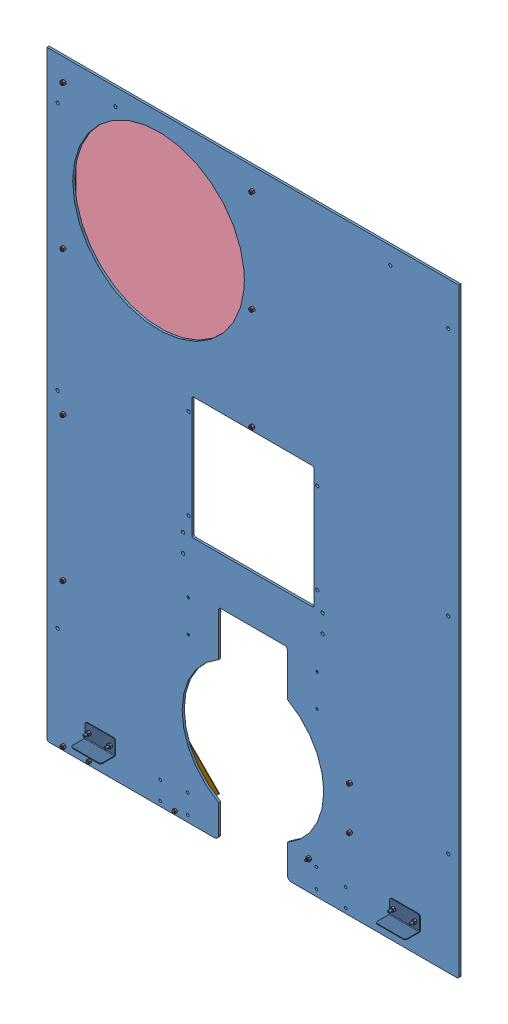
SolidWorks assembly GE-19156, configuration Default. Lengths in mm.
Overall size (1219.2 1778 85.73).
70 component instances, 22 part files, 143 mates.
Components (placement in the parent):
- GE-19157-4: GE-19157 [Default] at origin size (1219.2 1778 6.35)
- GE-19134-1: GE-19134 [Default] at (63.5 0 -6.35) x (-1 0 0) z (0 0 -1) size (25.4 1727.2 12.7)
- GE-19135-1: GE-19135 [Default] at (596.9 1098.55 -6.35) x (-1 0 0) z (0 0 -1) size (25.4 628.65 12.7)
- GE-19158-2: GE-19158 [Default] at (38.1 0 -28.575) size (584.2 1727.2 6.35)
- GE-19138-1: GE-19138 [Default] at (0 0 -19.05) size (406.4 120.65 12.7)
- GE-19139-2: GE-19139 [Default] at (1216.025 520.7 -31.75) x (-1 0 0) z (0 0 1) size (50.8 152.4 25.4)
- GE-19140-1: GE-19140 [Default] at (777.6052 88.9 -6.35) x (-0.923728 -0.383049 0) z (0 0 -1) size (25.4 25.4 25.4)
- GE-19190-1: GE-19190 [Default] at (838.1961 233.6306 -81.6653) x (0 0 -1) z (0 1 0) size (6.35 44.45 152.4)
  - GE-19190-1-1: GE-19190-1 [Default] at (-48.3278 -36.5164 -30.4306) size (6.35 19.05 152.4)
  - GE-19190-2-1: GE-19190-2 [Default] at (-50.709 -46.4642 60.9432) x (0 0 1) z (-1 0 0) size (152.4 28.57 3.17)
- GE-19190-2: GE-19190 [Default] at (371.4789 325.1694 -78.4903) x (0 0 -1) z (0 -1 0) size (6.35 44.45 152.4)
  - GE-19190-1-1: GE-19190-1 [Default] at (-48.3278 -36.5164 -30.4306) size (6.35 19.05 152.4)
  - GE-19190-2-1: GE-19190-2 [Default] at (-50.709 -46.4642 60.9432) x (0 0 1) z (-1 0 0) size (152.4 28.57 3.17)
- GE-19190-3: GE-19190 [Default] at (391.163 173.6734 -78.4903) x (0 0 -1) z (0.707107 -0.707107 0) size (6.35 44.45 152.4)
  - GE-19190-1-1: GE-19190-1 [Default] at (-48.3278 -36.5164 -30.4306) size (6.35 19.05 152.4)
  - GE-19190-2-1: GE-19190-2 [Default] at (-50.709 -46.4642 60.9432) x (0 0 1) z (-1 0 0) size (152.4 28.57 3.17)
- GE-19142-1: GE-19142 [Default] at (203.2 63.5 0) x (-1 0 0) z (0 0 -1) size (88.9 44.45 44.45)
- GE-19142-2: GE-19142 [Default] at (1104.9 63.5 0) x (-1 0 0) z (0 0 -1) size (88.9 44.45 44.45)
- hex_.25_20_1.5-1: hex_.25_20_1.5 [92865A546] at (50.8 1714.5 -11.5094) x (0 0 1) z (1 0 0) size (42.07 12.83 11.11)
- nylock_10_32-1: nylock_10_32 [90631A411] at (342.9 215.9 -30.1625) x (-0.98095 -0.194258 0) z (0.194258 -0.98095 0) size (9.53 5.95 11)
- nylock_.25_20-13: nylock_.25_20 [Default] at (1028.7 85.725 1.9812) x (-0.972777 -0.231744 0) z (-0.231744 0.972777 0) size (11.11 7.94 12.83)
- nylock_.25_20-14: nylock_.25_20 [Default] at (1092.2 85.725 1.9812) x (-0.994367 -0.105992 0) z (-0.105992 0.994367 0) size (11.11 7.94 12.83)
- nylock_.25_20-15: nylock_.25_20 [Default] at (127 85.725 1.9812) x (-0.999918 -0.012843 0) z (-0.012843 0.999918 0) size (11.11 7.94 12.83)
- nylock_.25_20-16: nylock_.25_20 [Default] at (190.5 85.725 1.9812) x (-0.999134 0.04161 0) z (0.04161 0.999134 0) size (11.11 7.94 12.83)
- flat_hex_.25_20_1-1: flat_hex_.25_20_1 [91253A542] at (1092.2 85.725 -6.35) x (1 0 0) z (0 0 -1) size (13.49 13.49 25.61)
- flat_hex_.25_20_1-2: flat_hex_.25_20_1 [91253A542] at (1028.7 85.725 -6.35) x (0.987351 -0.158553 0) z (0 0 -1) size (13.49 13.49 25.61)
- flat_hex_.25_20_1-3: flat_hex_.25_20_1 [91253A542] at (190.5 85.725 -6.35) x (0.959125 -0.282984 0) z (0 0 -1) size (13.49 13.49 25.61)
- flat_hex_.25_20_1-4: flat_hex_.25_20_1 [91253A542] at (127 85.725 -6.35) x (0.928571 -0.371154 0) z (0 0 -1) size (13.49 13.49 25.61)
- nylock_.25_20-17: nylock_.25_20 [Default] at (777.6052 88.9 0) x (0.809812 0.58669 0) z (0.58669 -0.809812 0) size (11.11 7.94 12.83)
- button_hex_.25_20_1.25-1: button_hex_.25_20_1.25 [Default] at (777.6052 88.9 -22.4028) x (0.923728 0.383049 0) z (0 0 -1) size (11.1 11.1 35.11)
- flat_hex_10_32_.625-1: flat_hex_10_32_.625 [Default] at (342.9 215.9 -22.225) x (0.923728 -0.383049 0) z (0 0 1) size (10.44 10.44 15.88)
- flat_hex_10_32_1.375-3: flat_hex_10_32_1.375 [Default] at (866.775 215.9 -6.35) x (-0.923728 0.383049 0) z (0 0 1) size (10.44 10.44 34.93)
- flat_hex_10_32_1.375-2: flat_hex_10_32_1.375 [Default] at (866.775 342.9 -6.35) x (-0.85131 0.524663 0) z (0 0 1) size (10.44 10.44 34.93)
- hex_.25_20_1.5-13: hex_.25_20_1.5 [92865A546] at (50.8 1289.05 -11.5094) x (0 0 1) z (0.987351 0.158553 0) size (42.07 12.83 11.11)
- hex_.25_20_1.5-14: hex_.25_20_1.5 [92865A546] at (50.8 863.6 -11.5094) x (0 0 1) z (0.959125 0.282984 0) size (42.07 12.83 11.11)
- hex_.25_20_1.5-15: hex_.25_20_1.5 [92865A546] at (50.8 438.15 -11.5094) x (0 0 1) z (0.928571 0.371154 0) size (42.07 12.83 11.11)
- hex_.25_20_1.5-16: hex_.25_20_1.5 [92865A546] at (50.8 12.7 -11.5094) x (0 0 1) z (0.906989 0.421154 0) size (42.07 12.83 11.11)
- hex_.25_20_1.5-19: hex_.25_20_1.5 [92865A546] at (609.6 1714.5 -11.5094) x (0 0 1) z (0.952324 0.305088 0) size (42.07 12.83 11.11)
- hex_.25_20_1.5-20: hex_.25_20_1.5 [92865A546] at (609.6 1412.875 -11.5094) x (0 0 1) z (0.985697 0.168526 0) size (42.07 12.83 11.11)
- hex_.25_20_1.5-21: hex_.25_20_1.5 [92865A546] at (609.6 1111.25 -11.5094) x (0 0 1) z (1 0 0) size (42.07 12.83 11.11)
- hex_.25_20_1.5-22: hex_.25_20_1.5 [92865A546] at (898.525 342.9 -14.6844) x (0 0 1) z (-0.845962 0.533243 0) size (42.07 12.83 11.11)
- hex_.25_20_1.5-24: hex_.25_20_1.5 [92865A546] at (898.525 215.9 -14.6844) x (0 0 1) z (-0.762825 0.646605 0) size (42.07 12.83 11.11)
- nylock_.25_20-18: nylock_.25_20 [Default] at (50.8 1714.5 0) x (1 0 0) z (0 -1 0) size (11.11 7.94 12.83)
- nylock_.25_20-19: nylock_.25_20 [Default] at (50.8 1289.05 0) x (0.987351 0.158553 0) z (0.158553 -0.987351 0) size (11.11 7.94 12.83)
- nylock_.25_20-20: nylock_.25_20 [Default] at (50.8 863.6 0) x (0.959125 0.282984 0) z (0.282984 -0.959125 0) size (11.11 7.94 12.83)
- nylock_.25_20-21: nylock_.25_20 [Default] at (50.8 438.15 0) x (0.928571 0.371154 0) z (0.371154 -0.928571 0) size (11.11 7.94 12.83)
- nylock_.25_20-22: nylock_.25_20 [Default] at (50.8 12.7 0) x (0.906989 0.421154 0) z (0.421154 -0.906989 0) size (11.11 7.94 12.83)
- nylock_.25_20-25: nylock_.25_20 [Default] at (609.6 1714.5 0) x (0.952324 0.305088 0) z (0.305088 -0.952324 0) size (11.11 7.94 12.83)
- nylock_.25_20-26: nylock_.25_20 [Default] at (609.6 1412.875 0) x (0.985697 0.168526 0) z (0.168526 -0.985697 0) size (11.11 7.94 12.83)
- nylock_.25_20-27: nylock_.25_20 [Default] at (609.6 1111.25 0) x (1 0 0) z (0 -1 0) size (11.11 7.94 12.83)
- nylock_.25_20-30: nylock_.25_20 [Default] at (898.525 342.9 0) x (0.987351 0.158553 0) z (0.158553 -0.987351 0) size (11.11 7.94 12.83)
- nylock_.25_20-32: nylock_.25_20 [Default] at (898.525 215.9 0) x (0.959125 0.282984 0) z (0.282984 -0.959125 0) size (11.11 7.94 12.83)
- nylock_10_32-12: nylock_10_32 [90631A411] at (342.9 342.9 -30.1625) x (-0.937742 -0.347333 0) z (0.347333 -0.937742 0) size (9.53 5.95 11)
- nylock_10_32-15: nylock_10_32 [90631A411] at (358.4172 166.0026 -30.1625) x (-0.885882 -0.463911 0) z (0.463911 -0.885882 0) size (9.53 5.95 11)
- nylock_10_32-14: nylock_10_32 [90631A411] at (448.2197 76.2 -30.1625) x (-0.838783 -0.544466 0) z (0.544466 -0.838783 0) size (9.53 5.95 11)
- nylock_10_32-13: nylock_10_32 [90631A411] at (866.775 342.9 -33.3375) x (-0.807899 -0.589321 0) z (0.589321 -0.807899 0) size (9.53 5.95 11)
- nylock_10_32-11: nylock_10_32 [90631A411] at (866.775 215.9 -33.3375) x (-0.802128 -0.597152 0) z (0.597152 -0.802128 0) size (9.53 5.95 11)
- flat_hex_10_32_.625-8: flat_hex_10_32_.625 [Default] at (342.9 342.9 -22.225) x (0.972777 -0.231744 0) z (0 0 1) size (10.44 10.44 15.88)
- flat_hex_10_32_.625-6: flat_hex_10_32_.625 [Default] at (358.4172 166.0026 -22.225) x (0.994367 -0.105992 0) z (0 0 1) size (10.44 10.44 15.88)
- flat_hex_10_32_.625-7: flat_hex_10_32_.625 [Default] at (448.2197 76.2 -22.225) x (0.999918 -0.012843 0) z (0 0 1) size (10.44 10.44 15.88)
- VisionTape-1: VisionTape [Default] at (795.3119 461.6361 -6.35) x (-0.968246 -0.25 0) z (0 0 -1) size (50.8 139.7 0.79)
- VisionTape-2: VisionTape [Default] at (473.075 448.9361 -6.35) x (-0.968246 0.25 0) z (0 0 -1) size (50.8 139.7 0.79)
- GE-19251-1: GE-19251 [Default] at (38.1 0 -22.225) size (25.4 1727.2 3.17)
- GE-19252-1: GE-19252 [Default] at (622.3 1098.55 -22.225) size (25.4 628.65 3.17)
- round_hex_flange_10_32_1.5_partial-1: round_hex_flange_10_32_1.5_partial [Default] at (381 12.7 -31.1404) x (-0.923728 -0.383049 0) z (0 0 -1) size (10.34 10.34 40.67)
- round_hex_flange_10_32_1.5_partial-2: round_hex_flange_10_32_1.5_partial [Default] at (127 12.7 -31.1404) x (-0.923728 -0.383049 0) z (0 0 -1) size (10.34 10.34 40.67)
- nylock_10_32-16: nylock_10_32 [90631A411] at (381 12.7 0) x (1 0 0) z (0 -1 0) size (9.53 5.95 11)
- nylock_10_32-17: nylock_10_32 [90631A411] at (127 12.7 0) x (1 0 0) z (0 -1 0) size (9.53 5.95 11)
- GE-19253-1: GE-19253 [92805K33] at (381 12.7 -28.575) x (-0.923728 -0.383049 0) z (-0.383049 0.923728 0) size (7.81 25.4 7.81)
- GE-19253-2: GE-19253 [92805K33] at (127 12.7 -28.575) x (-0.923728 -0.383049 0) z (-0.383049 0.923728 0) size (7.81 25.4 7.81)
Mates (geometry in assembly coordinates):
- Concentric4: concentric: cylinder of GE-19134-1 through (50.8 1714.5 -6.35) axis (0 0 -1) radius 3.3655; cylinder of GE-19157-4 through (50.8 1714.5 0) axis (0 0 -1) radius 3.3655
- Coincident9: coincident: plane of GE-19139-2 through (1216.025 520.7 -31.75) normal (0 0 -1); plane of GE-19190-1/GE-19190-1-1 through (860.425 355.6 -31.75) normal (0 0 1)
- Concentric10: concentric: cylinder of GE-19139-2 through (866.775 342.9 -6.35) axis (0 0 1) radius 2.8067; cylinder of GE-19190-1/GE-19190-1-1 through (866.775 342.9 -33.3375) axis (0 0 1) radius 2.5797
- Concentric11: concentric: cylinder of GE-19139-2 through (866.775 215.9 -6.35) axis (0 0 1) radius 2.8067; cylinder of GE-19190-1/GE-19190-1-1 through (866.775 215.9 -33.3375) axis (0 0 1) radius 2.5797
- Coincident10: coincident: plane of GE-19158-2 through (38.1 0 -28.575) normal (0 0 -1); plane of GE-19190-2/GE-19190-1-1 through (349.25 203.2 -28.575) normal (0 0 1)
- Coincident11: coincident: plane of GE-19158-2 through (38.1 0 -28.575) normal (0 0 -1); plane of GE-19190-3/GE-19190-1-1 through (461.6901 71.7099 -28.575) normal (0 0 1)
- Concentric14: concentric: cylinder of GE-19158-2 through (358.4172 166.0026 -22.225) axis (0 0 1) radius 2.8067; cylinder of GE-19190-3/GE-19190-1-1 through (358.4172 166.0026 -30.1625) axis (0 0 1) radius 2.5797
- Concentric15: concentric: cylinder of GE-19190-3/GE-19190-1-1 through (448.2197 76.2 -30.1625) axis (0 0 1) radius 2.5797; cylinder of GE-19158-2 through (448.2197 76.2 -22.225) axis (0 0 1) radius 2.8067
- Coincident14: coincident: plane of assembly; plane of assembly; plane of GE-19158-2 through (38.1 0 -28.575) normal (0 0 -1); plane of hex_.25_20_1.5-1 through (56.3562 1711.2921 -28.575) normal (0 0 1)
- Concentric19: concentric: cylinder of assembly; cylinder of assembly; cylinder of GE-19158-2 through (50.8 1714.5 -22.225) axis (0 0 1) radius 3.3782; cylinder of hex_.25_20_1.5-1 through (50.8 1714.5 -28.575) axis (0 0 1) radius 3.175
- Concentric43: concentric: cylinder of GE-19190-2/GE-19190-1-1 through (342.9 215.9 -30.1625) axis (0 0 1) radius 2.5797; cylinder of nylock_10_32-1 through (342.9 215.9 -35.1996) axis (0 0 1) radius 2.0454
- Coincident42: coincident: plane of GE-19190-2/GE-19190-1-1 through (354.0125 203.2 -30.1625) normal (0 0 -1); plane of nylock_10_32-1 through (341.8317 221.2945 -30.1625) normal (0 0 1)
- Concentric44: concentric: cylinder of assembly; cylinder of assembly; cylinder of nylock_10_32-1 through (342.9 215.9 -35.1996) axis (0 0 1) radius 2.0454; cylinder of flat_hex_10_32_.625-1 through (342.9 215.9 -22.225) axis (0 0 1) radius 5.2197
- Coincident50: coincident: plane of assembly; plane of assembly; plane of GE-19142-2 through (1016 65.4812 1.9812) normal (0 0 1); plane of nylock_.25_20-13 through (1028.7 85.725 1.9812) normal (0 0 -1)
- Concentric55: concentric: cylinder of assembly; cylinder of assembly; cylinder of GE-19142-2 through (1028.7 85.725 88.9) axis (0 0 -1) radius 3.3782; cylinder of nylock_.25_20-13 through (1028.7 85.725 1.9812) axis (0 0 1) radius 3.175
- Coincident51: coincident: plane of assembly; plane of assembly; plane of GE-19142-2 through (1016 65.4812 1.9812) normal (0 0 1); plane of nylock_.25_20-14 through (1092.2 85.725 1.9812) normal (0 0 -1)
- Concentric56: concentric: cylinder of assembly; cylinder of assembly; cylinder of GE-19142-2 through (1092.2 85.725 88.9) axis (0 0 -1) radius 3.3782; cylinder of nylock_.25_20-14 through (1092.2 85.725 1.9812) axis (0 0 1) radius 3.175
- Coincident52: coincident: plane of assembly; plane of assembly; plane of GE-19142-1 through (114.3 65.4812 1.9812) normal (0 0 1); plane of nylock_.25_20-15 through (127 85.725 1.9812) normal (0 0 -1)
- Concentric57: concentric: cylinder of assembly; cylinder of assembly; cylinder of GE-19142-1 through (127 85.725 88.9) axis (0 0 -1) radius 3.3782; cylinder of nylock_.25_20-15 through (127 85.725 1.9812) axis (0 0 1) radius 3.175
- Coincident53: coincident: plane of assembly; plane of assembly; plane of GE-19142-1 through (114.3 65.4812 1.9812) normal (0 0 1); plane of nylock_.25_20-16 through (190.5 85.725 1.9812) normal (0 0 -1)
- Concentric58: concentric: cylinder of assembly; cylinder of assembly; cylinder of GE-19142-1 through (190.5 85.725 88.9) axis (0 0 -1) radius 3.3782; cylinder of nylock_.25_20-16 through (190.5 85.725 1.9812) axis (0 0 1) radius 3.175
- Concentric59: concentric: cylinder of assembly; cylinder of assembly; cylinder of GE-19142-2 through (1092.2 85.725 88.9) axis (0 0 -1) radius 3.3782; cylinder of flat_hex_.25_20_1-1 through (1092.2 85.725 19.05) axis (0 0 1) radius 3.175
- Concentric60: concentric: cylinder of assembly; cylinder of assembly; cylinder of GE-19142-2 through (1028.7 85.725 88.9) axis (0 0 -1) radius 3.3782; cylinder of flat_hex_.25_20_1-2 through (1028.7 85.725 19.05) axis (0 0 1) radius 3.175
- Concentric61: concentric: cylinder of assembly; cylinder of assembly; cylinder of GE-19142-1 through (190.5 85.725 88.9) axis (0 0 -1) radius 3.3782; cylinder of flat_hex_.25_20_1-3 through (190.5 85.725 19.05) axis (0 0 1) radius 3.175
- Concentric62: concentric: cylinder of assembly; cylinder of assembly; cylinder of GE-19142-1 through (127 85.725 88.9) axis (0 0 -1) radius 3.3782; cylinder of flat_hex_.25_20_1-4 through (127 85.725 19.05) axis (0 0 1) radius 3.175
- Coincident61: coincident: plane of assembly; plane of assembly; plane of GE-19140-1 through (777.6052 88.9 -19.05) normal (0 0 -1); plane of button_hex_.25_20_1.25-1 through (775.4793 94.0266 -19.05) normal (0 0 1)
- Concentric64: concentric: cylinder of assembly; cylinder of assembly; cylinder of GE-19140-1 through (777.6052 88.9 -19.05) axis (0 0 -1) radius 5.5563; cylinder of button_hex_.25_20_1.25-1 through (777.6052 88.9 -22.4028) axis (0 0 -1) radius 5.5499
- Coincident62: coincident: plane of assembly; plane of assembly; plane of flat_hex_10_32_.625-1 through (341.9757 213.671 -22.225) normal (0 0 1); plane of GE-19158-2 through (38.1 0 -22.225) normal (0 0 1)
- Coincident67: coincident: plane of assembly; plane of assembly; plane of GE-19139-2 through (1216.025 520.7 -6.35) normal (0 0 1); plane of flat_hex_10_32_1.375-3 through (866.775 215.9 -6.35) normal (0 0 1)
- Coincident68: coincident: plane of assembly; plane of assembly; plane of GE-19139-2 through (1216.025 520.7 -6.35) normal (0 0 1); plane of flat_hex_10_32_1.375-2 through (866.775 342.9 -6.35) normal (0 0 1)
- Coincident69: coincident: plane of GE-19157-4 through (0 0 -6.35) normal (0 0 -1); plane of GE-19134-1 through (63.5 0 -6.35) normal (0 0 1)
- Concentric65: concentric: cylinder of GE-19157-4 through (50.8 12.7 0) axis (0 0 -1) radius 3.3655; cylinder of GE-19134-1 through (50.8 12.7 -6.35) axis (0 0 -1) radius 3.3655
- Coincident70: coincident: plane of GE-19157-4 through (0 0 -6.35) normal (0 0 -1); plane of GE-19135-1 through (596.9 1098.55 -6.35) normal (0 0 1)
- Concentric66: concentric: cylinder of GE-19157-4 through (609.6 1714.5 0) axis (0 0 -1) radius 3.429; cylinder of GE-19135-1 through (609.6 1714.5 -6.35) axis (0 0 -1) radius 3.3655
- Concentric67: concentric: cylinder of GE-19157-4 through (609.6 1111.25 0) axis (0 0 -1) radius 3.429; cylinder of GE-19135-1 through (609.6 1111.25 -6.35) axis (0 0 -1) radius 3.3655
- Coincident71: coincident: plane of assembly; plane of assembly; plane of GE-19158-2 through (38.1 0 -22.225) normal (0 0 1); plane of GE-19251-1 through (38.1 0 -22.225) normal (0 0 -1)
- Concentric68: concentric: cylinder of assembly; cylinder of assembly; cylinder of GE-19134-1 through (50.8 1714.5 -6.35) axis (0 0 -1) radius 3.3655; cylinder of GE-19158-2 through (50.8 1714.5 -22.225) axis (0 0 1) radius 3.3782
- Concentric69: concentric: cylinder of assembly; cylinder of assembly; cylinder of GE-19135-1 through (609.6 1714.5 -6.35) axis (0 0 -1) radius 3.3655; cylinder of GE-19158-2 through (609.6 1714.5 -22.225) axis (0 0 1) radius 3.3782
- Coincident72: coincident: plane of GE-19157-4 through (0 0 -6.35) normal (0 0 -1); plane of GE-19138-1 through (457.2 76.2 -6.35) normal (0 0 1)
- Concentric70: concentric: cylinder of assembly; cylinder of assembly; cylinder of GE-19158-2 through (127 12.7 -34.925) axis (0 0 1) radius 3.9688; cylinder of GE-19138-1 through (127 12.7 -19.05) axis (0 0 1) radius 3.9688
- Concentric71: concentric: cylinder of assembly; cylinder of assembly; cylinder of GE-19158-2 through (381 12.7 -34.925) axis (0 0 1) radius 3.9688; cylinder of GE-19138-1 through (381 12.7 -19.05) axis (0 0 1) radius 3.9688
- Coincident73: coincident: plane of GE-19157-4 through (0 0 -6.35) normal (0 0 -1); plane of GE-19139-2 through (1216.025 520.7 -6.35) normal (0 0 1)
- Concentric72: concentric: cylinder of GE-19157-4 through (898.525 215.9 0) axis (0 0 -1) radius 3.3782; cylinder of GE-19139-2 through (898.525 215.9 -6.35) axis (0 0 -1) radius 3.3782
- Concentric73: concentric: cylinder of GE-19157-4 through (898.525 342.9 0) axis (0 0 -1) radius 3.3782; cylinder of GE-19139-2 through (898.525 342.9 -6.35) axis (0 0 -1) radius 3.3782
- Coincident74: coincident: plane of GE-19157-4 through (0 0 -6.35) normal (0 0 -1); plane of GE-19140-1 through (777.6052 88.9 -6.35) normal (0 0 1)
- Concentric74: concentric: cylinder of GE-19157-4 through (777.6052 88.9 0) axis (0 0 -1) radius 3.3782; cylinder of GE-19140-1 through (777.6052 88.9 -31.75) axis (0 0 1) radius 12.7
- Concentric75: concentric: cylinder of GE-19158-2 through (342.9 342.9 -22.225) axis (0 0 1) radius 2.8067; cylinder of GE-19190-2/GE-19190-1-1 through (342.9 342.9 -30.1625) axis (0 0 1) radius 2.5797
- Concentric76: concentric: cylinder of GE-19158-2 through (342.9 215.9 -22.225) axis (0 0 1) radius 2.8067; cylinder of GE-19190-2/GE-19190-1-1 through (342.9 215.9 -30.1625) axis (0 0 1) radius 2.5797
- Coincident75: coincident: plane of GE-19157-4 through (0 0 0) normal (0 0 1); plane of GE-19142-1 through (114.3 107.95 0) normal (0 0 -1)
- Concentric77: concentric: cylinder of GE-19157-4 through (127 85.725 -6.35) axis (0 0 -1) radius 3.5712; cylinder of GE-19142-1 through (127 85.725 88.9) axis (0 0 -1) radius 3.3782
- Concentric78: concentric: cylinder of GE-19157-4 through (190.5 85.725 -6.35) axis (0 0 -1) radius 3.5712; cylinder of GE-19142-1 through (190.5 85.725 88.9) axis (0 0 -1) radius 3.3782
- Coincident76: coincident: plane of GE-19157-4 through (0 0 0) normal (0 0 1); plane of GE-19142-2 through (1016 107.95 0) normal (0 0 -1)
- Concentric79: concentric: cylinder of GE-19157-4 through (1028.7 85.725 -6.35) axis (0 0 -1) radius 3.5712; cylinder of GE-19142-2 through (1028.7 85.725 88.9) axis (0 0 -1) radius 3.3782
- Concentric80: concentric: cylinder of GE-19157-4 through (1092.2 85.725 -6.35) axis (0 0 -1) radius 3.5712; cylinder of GE-19142-2 through (1092.2 85.725 88.9) axis (0 0 -1) radius 3.3782
- Coincident77: coincident: plane of assembly; plane of assembly; plane of GE-19158-2 through (38.1 0 -28.575) normal (0 0 -1); plane of hex_.25_20_1.5-13 through (56.7946 1286.7636 -28.575) normal (0 0 1)
- Concentric81: concentric: cylinder of assembly; cylinder of assembly; cylinder of GE-19158-2 through (50.8 1289.05 -22.225) axis (0 0 1) radius 3.3782; cylinder of hex_.25_20_1.5-13 through (50.8 1289.05 -28.575) axis (0 0 1) radius 3.175
- Coincident78: coincident: plane of assembly; plane of assembly; plane of GE-19158-2 through (38.1 0 -28.575) normal (0 0 -1); plane of hex_.25_20_1.5-14 through (57.0369 862.0955 -28.575) normal (0 0 1)
- Concentric82: concentric: cylinder of assembly; cylinder of assembly; cylinder of GE-19158-2 through (50.8 863.6 -22.225) axis (0 0 1) radius 3.3782; cylinder of hex_.25_20_1.5-14 through (50.8 863.6 -28.575) axis (0 0 1) radius 3.175
- Coincident79: coincident: plane of assembly; plane of assembly; plane of GE-19158-2 through (38.1 0 -28.575) normal (0 0 -1); plane of hex_.25_20_1.5-15 through (57.15 437.2335 -28.575) normal (0 0 1)
- Concentric83: concentric: cylinder of assembly; cylinder of assembly; cylinder of GE-19158-2 through (50.8 438.15 -22.225) axis (0 0 1) radius 3.3782; cylinder of hex_.25_20_1.5-15 through (50.8 438.15 -28.575) axis (0 0 1) radius 3.175
- Coincident80: coincident: plane of assembly; plane of assembly; plane of GE-19158-2 through (38.1 0 -28.575) normal (0 0 -1); plane of hex_.25_20_1.5-16 through (57.1905 12.1305 -28.575) normal (0 0 1)
- Concentric84: concentric: cylinder of assembly; cylinder of assembly; cylinder of GE-19158-2 through (50.8 12.7 -22.225) axis (0 0 1) radius 3.3782; cylinder of hex_.25_20_1.5-16 through (50.8 12.7 -28.575) axis (0 0 1) radius 3.175
- Coincident83: coincident: plane of assembly; plane of assembly; plane of GE-19158-2 through (38.1 0 -28.575) normal (0 0 -1); plane of hex_.25_20_1.5-19 through (615.87 1713.1402 -28.575) normal (0 0 1)
- Concentric87: concentric: cylinder of assembly; cylinder of assembly; cylinder of GE-19158-2 through (609.6 1714.5 -22.225) axis (0 0 1) radius 3.3782; cylinder of hex_.25_20_1.5-19 through (609.6 1714.5 -28.575) axis (0 0 1) radius 3.175
- Coincident84: coincident: plane of assembly; plane of assembly; plane of GE-19158-2 through (38.1 0 -28.575) normal (0 0 -1); plane of hex_.25_20_1.5-20 through (615.6174 1410.6494 -28.575) normal (0 0 1)
- Concentric88: concentric: cylinder of assembly; cylinder of assembly; cylinder of GE-19158-2 through (609.6 1412.875 -22.225) axis (0 0 1) radius 3.3782; cylinder of hex_.25_20_1.5-20 through (609.6 1412.875 -28.575) axis (0 0 1) radius 3.175
- Coincident85: coincident: plane of assembly; plane of assembly; plane of GE-19158-2 through (38.1 0 -28.575) normal (0 0 -1); plane of hex_.25_20_1.5-21 through (615.1562 1108.0421 -28.575) normal (0 0 1)
- Concentric89: concentric: cylinder of assembly; cylinder of assembly; cylinder of GE-19158-2 through (609.6 1111.25 -22.225) axis (0 0 1) radius 3.3782; cylinder of hex_.25_20_1.5-21 through (609.6 1111.25 -28.575) axis (0 0 1) radius 3.175
- Concentric90: concentric: cylinder of assembly; cylinder of assembly; cylinder of GE-19139-2 through (898.525 342.9 -6.35) axis (0 0 -1) radius 3.3782; cylinder of hex_.25_20_1.5-22 through (898.525 342.9 -31.75) axis (0 0 1) radius 3.175
- Coincident87: coincident: plane of assembly; plane of assembly; plane of GE-19139-2 through (1216.025 520.7 -31.75) normal (0 0 -1); plane of hex_.25_20_1.5-22 through (895.5352 348.5766 -31.75) normal (0 0 1)
- Coincident88: coincident: plane of assembly; plane of assembly; plane of GE-19139-2 through (1216.025 520.7 -31.75) normal (0 0 -1); plane of hex_.25_20_1.5-24 through (896.3608 221.9398 -31.75) normal (0 0 1)
- Concentric91: concentric: cylinder of assembly; cylinder of assembly; cylinder of GE-19139-2 through (898.525 215.9 -6.35) axis (0 0 -1) radius 3.3782; cylinder of hex_.25_20_1.5-24 through (898.525 215.9 -31.75) axis (0 0 1) radius 3.175
- Concentric92: concentric: cylinder of assembly; cylinder of assembly; cylinder of hex_.25_20_1.5-1 through (50.8 1714.5 -28.575) axis (0 0 1) radius 3.175; cylinder of nylock_.25_20-18 through (50.8 1714.5 0) axis (0 0 -1) radius 2.6162
- Coincident89: coincident: plane of GE-19157-4 through (0 0 0) normal (0 0 1); plane of nylock_.25_20-18 through (50.8 1714.5 0) normal (0 0 -1)
- Coincident90: coincident: plane of GE-19157-4 through (0 0 0) normal (0 0 1); plane of nylock_.25_20-19 through (50.8 1289.05 0) normal (0 0 -1)
- Concentric93: concentric: cylinder of assembly; cylinder of assembly; cylinder of hex_.25_20_1.5-13 through (50.8 1289.05 -28.575) axis (0 0 1) radius 3.175; cylinder of nylock_.25_20-19 through (50.8 1289.05 0) axis (0 0 -1) radius 2.6162
- Coincident91: coincident: plane of GE-19157-4 through (0 0 0) normal (0 0 1); plane of nylock_.25_20-20 through (50.8 863.6 0) normal (0 0 -1)
- Concentric94: concentric: cylinder of assembly; cylinder of assembly; cylinder of hex_.25_20_1.5-14 through (50.8 863.6 -28.575) axis (0 0 1) radius 3.175; cylinder of nylock_.25_20-20 through (50.8 863.6 0) axis (0 0 -1) radius 2.6162
- Coincident92: coincident: plane of GE-19157-4 through (0 0 0) normal (0 0 1); plane of nylock_.25_20-21 through (50.8 438.15 0) normal (0 0 -1)
- Concentric95: concentric: cylinder of assembly; cylinder of assembly; cylinder of hex_.25_20_1.5-15 through (50.8 438.15 -28.575) axis (0 0 1) radius 3.175; cylinder of nylock_.25_20-21 through (50.8 438.15 0) axis (0 0 -1) radius 2.6162
- Coincident93: coincident: plane of GE-19157-4 through (0 0 0) normal (0 0 1); plane of nylock_.25_20-22 through (50.8 12.7 0) normal (0 0 -1)
- Concentric96: concentric: cylinder of assembly; cylinder of assembly; cylinder of hex_.25_20_1.5-16 through (50.8 12.7 -28.575) axis (0 0 1) radius 3.175; cylinder of nylock_.25_20-22 through (50.8 12.7 0) axis (0 0 -1) radius 2.6162
- Coincident96: coincident: plane of GE-19157-4 through (0 0 0) normal (0 0 1); plane of nylock_.25_20-25 through (609.6 1714.5 0) normal (0 0 -1)
- Concentric99: concentric: cylinder of assembly; cylinder of assembly; cylinder of hex_.25_20_1.5-19 through (609.6 1714.5 -28.575) axis (0 0 1) radius 3.175; cylinder of nylock_.25_20-25 through (609.6 1714.5 0) axis (0 0 -1) radius 2.6162
- Coincident97: coincident: plane of GE-19157-4 through (0 0 0) normal (0 0 1); plane of nylock_.25_20-26 through (609.6 1412.875 0) normal (0 0 -1)
- Concentric100: concentric: cylinder of assembly; cylinder of assembly; cylinder of hex_.25_20_1.5-20 through (609.6 1412.875 -28.575) axis (0 0 1) radius 3.175; cylinder of nylock_.25_20-26 through (609.6 1412.875 0) axis (0 0 -1) radius 2.6162
- Coincident98: coincident: plane of GE-19157-4 through (0 0 0) normal (0 0 1); plane of nylock_.25_20-27 through (609.6 1111.25 0) normal (0 0 -1)
- Concentric101: concentric: cylinder of assembly; cylinder of assembly; cylinder of hex_.25_20_1.5-21 through (609.6 1111.25 -28.575) axis (0 0 1) radius 3.175; cylinder of nylock_.25_20-27 through (609.6 1111.25 0) axis (0 0 -1) radius 2.6162
- Concentric102: concentric: cylinder of assembly; cylinder of assembly; cylinder of hex_.25_20_1.5-22 through (898.525 342.9 -31.75) axis (0 0 1) radius 3.175; cylinder of nylock_.25_20-30 through (898.525 342.9 0) axis (0 0 -1) radius 2.6162
- Coincident102: coincident: plane of GE-19157-4 through (0 0 0) normal (0 0 1); plane of nylock_.25_20-30 through (898.525 342.9 0) normal (0 0 -1)
- Coincident103: coincident: plane of GE-19157-4 through (0 0 0) normal (0 0 1); plane of nylock_.25_20-32 through (898.525 215.9 0) normal (0 0 -1)
- Concentric103: concentric: cylinder of assembly; cylinder of assembly; cylinder of hex_.25_20_1.5-24 through (898.525 215.9 -31.75) axis (0 0 1) radius 3.175; cylinder of nylock_.25_20-32 through (898.525 215.9 0) axis (0 0 -1) radius 2.6162
- Coincident104: coincident: plane of GE-19190-2/GE-19190-1-1 through (354.0125 203.2 -30.1625) normal (0 0 -1); plane of nylock_10_32-12 through (340.9899 348.0569 -30.1625) normal (0 0 1)
- Concentric104: concentric: cylinder of GE-19190-2/GE-19190-1-1 through (342.9 342.9 -30.1625) axis (0 0 1) radius 2.5797; cylinder of nylock_10_32-12 through (342.9 342.9 -35.1996) axis (0 0 1) radius 2.0454
- Coincident105: coincident: plane of GE-19190-2/GE-19190-1-1 through (354.0125 203.2 -30.1625) normal (0 0 -1); plane of nylock_10_32-15 through (355.866 170.8743 -30.1625) normal (0 0 1)
- Concentric105: concentric: cylinder of GE-19190-3/GE-19190-1-1 through (358.4172 166.0026 -30.1625) axis (0 0 1) radius 2.5797; cylinder of nylock_10_32-15 through (358.4172 166.0026 -35.1996) axis (0 0 1) radius 2.0454
- Coincident106: coincident: plane of GE-19190-2/GE-19190-1-1 through (354.0125 203.2 -30.1625) normal (0 0 -1); plane of nylock_10_32-14 through (445.2256 80.8127 -30.1625) normal (0 0 1)
- Concentric106: concentric: cylinder of GE-19190-3/GE-19190-1-1 through (448.2197 76.2 -30.1625) axis (0 0 1) radius 2.5797; cylinder of nylock_10_32-14 through (448.2197 76.2 -35.1996) axis (0 0 1) radius 2.0454
- Coincident107: coincident: plane of GE-19190-1/GE-19190-1-1 through (855.6625 355.6 -33.3375) normal (0 0 -1); plane of nylock_10_32-13 through (863.5342 347.3428 -33.3375) normal (0 0 1)
- Concentric107: concentric: cylinder of GE-19190-1/GE-19190-1-1 through (866.775 342.9 -33.3375) axis (0 0 1) radius 2.5797; cylinder of nylock_10_32-13 through (866.775 342.9 -38.3746) axis (0 0 1) radius 2.0454
- Concentric108: concentric: cylinder of GE-19190-1/GE-19190-1-1 through (866.775 215.9 -33.3375) axis (0 0 1) radius 2.5797; cylinder of nylock_10_32-11 through (866.775 215.9 -38.3746) axis (0 0 1) radius 2.0454
- Coincident109: coincident: plane of GE-19190-1/GE-19190-1-1 through (855.6625 355.6 -33.3375) normal (0 0 -1); plane of nylock_10_32-11 through (863.4911 220.3111 -33.3375) normal (0 0 1)
- Coincident110: coincident: plane of GE-19157-4 through (0 0 -6.35) normal (0 0 -1); plane of flat_hex_.25_20_1-1 through (1092.2 88.9 -6.35) normal (0 0 -1)
- Coincident111: coincident: plane of GE-19157-4 through (0 0 -6.35) normal (0 0 -1); plane of flat_hex_.25_20_1-2 through (1029.2034 88.8598 -6.35) normal (0 0 -1)
- Coincident112: coincident: plane of GE-19157-4 through (0 0 -6.35) normal (0 0 -1); plane of flat_hex_.25_20_1-3 through (191.3985 88.7702 -6.35) normal (0 0 -1)
- Coincident113: coincident: plane of GE-19157-4 through (0 0 -6.35) normal (0 0 -1); plane of flat_hex_.25_20_1-4 through (128.1784 88.6732 -6.35) normal (0 0 -1)
- Concentric109: concentric: cylinder of GE-19157-4 through (777.6052 88.9 0) axis (0 0 -1) radius 3.3782; cylinder of nylock_.25_20-17 through (777.6052 88.9 0) axis (0 0 1) radius 3.175
- Coincident114: coincident: plane of GE-19157-4 through (0 0 0) normal (0 0 1); plane of nylock_.25_20-17 through (777.6052 88.9 0) normal (0 0 -1)
- Coincident115: coincident: plane of assembly; plane of assembly; plane of GE-19158-2 through (38.1 0 -22.225) normal (0 0 1); plane of flat_hex_10_32_.625-1 through (341.9757 213.671 -22.225) normal (0 0 1)
- Concentric110: concentric: cylinder of assembly; cylinder of assembly; cylinder of nylock_10_32-12 through (342.9 342.9 -35.1996) axis (0 0 1) radius 2.0454; cylinder of flat_hex_10_32_.625-8 through (342.9 342.9 -22.225) axis (0 0 1) radius 5.2197
- Coincident116: coincident: plane of assembly; plane of assembly; plane of GE-19158-2 through (38.1 0 -22.225) normal (0 0 1); plane of flat_hex_10_32_.625-6 through (358.1614 163.6032 -22.225) normal (0 0 1)
- Concentric111: concentric: cylinder of assembly; cylinder of assembly; cylinder of nylock_10_32-15 through (358.4172 166.0026 -35.1996) axis (0 0 1) radius 2.0454; cylinder of flat_hex_10_32_.625-6 through (358.4172 166.0026 -22.225) axis (0 0 1) radius 5.2197
- Coincident117: coincident: plane of assembly; plane of assembly; plane of GE-19158-2 through (38.1 0 -22.225) normal (0 0 1); plane of flat_hex_10_32_.625-7 through (448.1888 73.7872 -22.225) normal (0 0 1)
- Concentric112: concentric: cylinder of assembly; cylinder of assembly; cylinder of nylock_10_32-14 through (448.2197 76.2 -35.1996) axis (0 0 1) radius 2.0454; cylinder of flat_hex_10_32_.625-7 through (448.2197 76.2 -22.225) axis (0 0 1) radius 5.2197
- Concentric113: concentric: cylinder of assembly; cylinder of assembly; cylinder of GE-19139-2 through (866.775 215.9 -6.35) axis (0 0 1) radius 2.8067; cylinder of flat_hex_10_32_1.375-3 through (866.775 215.9 -6.35) axis (0 0 1) radius 5.2197
- Concentric114: concentric: cylinder of assembly; cylinder of assembly; cylinder of GE-19139-2 through (866.775 342.9 -6.35) axis (0 0 1) radius 2.8067; cylinder of flat_hex_10_32_1.375-2 through (866.775 342.9 -6.35) axis (0 0 1) radius 5.2197
- Coincident160: coincident: plane of GE-19157-4 through (0 0 -6.35) normal (0 0 -1); plane of VisionTape-1 through (795.3119 461.6361 -6.35) normal (0 0 1)
- Coincident162: coincident: line of GE-19157-4; line of VisionTape-1 through (760.3869 596.9 -7.1437) axis (0 0 1)
- Coincident163: coincident: plane of GE-19157-4 through (711.2 596.9 0) normal (-1 0 0); line of VisionTape-1 through (711.2 584.2 -7.1437) axis (0 0 1)
- Distance7: distance = 12.7 mm: line of VisionTape-1 through (711.2 584.2 -7.1437) axis (0 0 1); plane of GE-19157-4 through (508 596.9 0) normal (0 -1 0)
- Coincident161: coincident: plane of GE-19157-4 through (0 0 -6.35) normal (0 0 -1); plane of VisionTape-2 through (473.075 448.9361 -6.35) normal (0 0 1)
- Coincident165: coincident: plane of GE-19157-4 through (508 596.9 0) normal (1 0 0); line of VisionTape-2 through (508 584.2 -7.1437) axis (0 0 1)
- Coincident166: coincident: plane of GE-19157-4 through (508 596.9 0) normal (0 -1 0); line of VisionTape-2 through (458.8131 596.9 -7.1437) axis (0 0 1)
- Distance8: distance = 12.7 mm: line of VisionTape-2 through (508 584.2 -7.1437) axis (0 0 1); plane of GE-19157-4 through (508 596.9 0) normal (0 -1 0)
- Coincident167: coincident: plane of assembly; plane of assembly; plane of GE-19158-2 through (38.1 0 -22.225) normal (0 0 1); plane of flat_hex_10_32_.625-8 through (342.3408 340.5527 -22.225) normal (0 0 1)
- Coincident168: coincident: plane of assembly; plane of assembly; plane of GE-19134-1 through (63.5 0 -19.05) normal (0 0 -1); plane of GE-19251-1 through (38.1 0 -19.05) normal (0 0 1)
- Coincident169: coincident: plane of assembly; plane of assembly; plane of GE-19134-1 through (38.1 0 -19.05) normal (-1 0 0); plane of GE-19251-1 through (38.1 1727.2 -19.05) normal (-1 0 0)
- Coincident170: coincident: plane of assembly; plane of assembly; plane of GE-19134-1 through (63.5 1727.2 -19.05) normal (0 1 0); plane of GE-19251-1 through (38.1 1727.2 -19.05) normal (0 1 0)
- Coincident172: coincident: plane of assembly; plane of assembly; plane of GE-19135-1 through (596.9 1098.55 -19.05) normal (0 0 -1); plane of GE-19252-1 through (622.3 1098.55 -19.05) normal (0 0 1)
- Coincident173: coincident: plane of assembly; plane of assembly; plane of GE-19135-1 through (596.9 1098.55 -19.05) normal (-1 0 0); plane of GE-19252-1 through (596.9 1098.55 -19.05) normal (-1 0 0)
- Coincident174: coincident: plane of assembly; plane of assembly; plane of GE-19135-1 through (596.9 1727.2 -19.05) normal (0 1 0); plane of GE-19252-1 through (622.3 1727.2 -19.05) normal (0 1 0)
- Concentric115: concentric: circle of assembly; circle of assembly; circle of round_hex_flange_10_32_1.5_partial-1; circle of GE-19253-1
- Coincident175: coincident: plane of assembly; plane of assembly; plane of round_hex_flange_10_32_1.5_partial-1 through (382.7562 8.465 -28.575) normal (0 0 1); plane of GE-19253-1 through (378.8004 11.7879 -28.575) normal (0 0 -1)
- Concentric116: concentric: circle of assembly; circle of assembly; circle of GE-19158-2; circle of GE-19253-1
- Coincident176: coincident: plane of assembly; plane of assembly; plane of GE-19158-2 through (38.1 0 -28.575) normal (0 0 -1); plane of round_hex_flange_10_32_1.5_partial-1 through (382.7562 8.465 -28.575) normal (0 0 1)
- Coincident177: coincident: plane of GE-19157-4 through (0 0 0) normal (0 0 1); plane of nylock_10_32-16 through (381 18.1993 0) normal (0 0 -1)
- Concentric118: concentric: circle of GE-19157-4; circle of nylock_10_32-16
- Concentric119: concentric: circle of assembly; circle of assembly; circle of round_hex_flange_10_32_1.5_partial-2; circle of GE-19253-2
- Coincident178: coincident: plane of assembly; plane of assembly; plane of round_hex_flange_10_32_1.5_partial-2 through (128.7562 8.465 -28.575) normal (0 0 1); plane of GE-19253-2 through (124.8004 11.7879 -28.575) normal (0 0 -1)
- Concentric120: concentric: circle of assembly; circle of assembly; circle of GE-19158-2; circle of GE-19253-2
- Coincident179: coincident: plane of assembly; plane of assembly; plane of GE-19158-2 through (38.1 0 -28.575) normal (0 0 -1); plane of round_hex_flange_10_32_1.5_partial-2 through (128.7562 8.465 -28.575) normal (0 0 1)
- Concentric121: concentric: circle of GE-19157-4; circle of nylock_10_32-17
- Coincident180: coincident: plane of GE-19157-4 through (0 0 0) normal (0 0 1); plane of nylock_10_32-17 through (127 18.1993 0) normal (0 0 -1)
